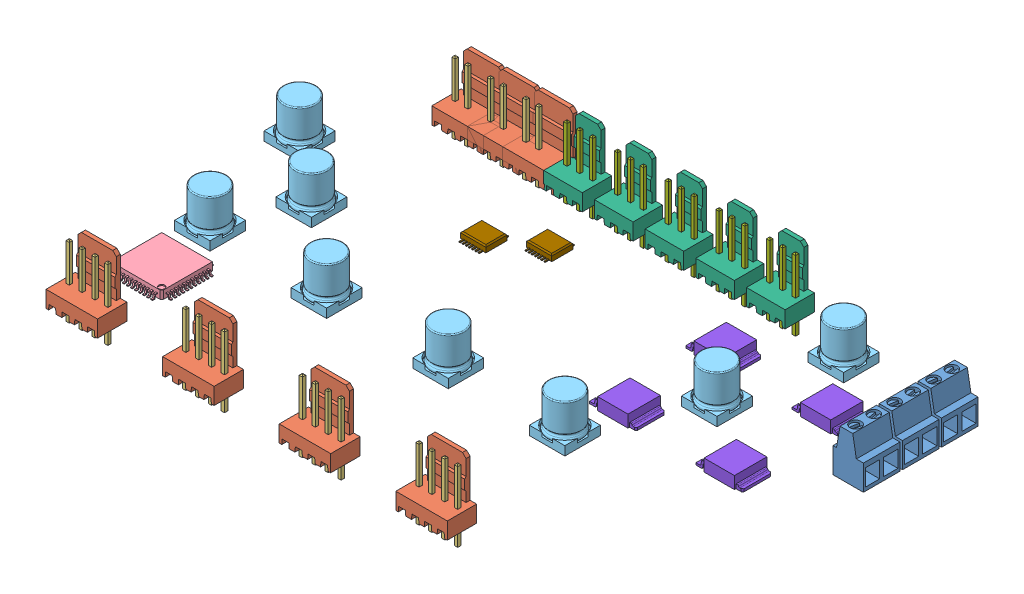
SolidWorks assembly Duex5, configuration Default. Lengths in mm.
Overall size (119.17 14.96 75.22).
91 component instances, 9 part files, 0 mates.
Components (placement in the parent):
- Duet WiFi v1-1: Duet WiFi v1 [Default] at origin (suppressed, hidden)
- 2 pole terminal block v7-1: 2 pole terminal block v7 [Default] at (58.1029 1.6572 -18.2256) x (0 0 -1) z (1 0 0) size (7.2 9 6)
- 2 pole terminal block v7-2: 2 pole terminal block v7 [Default] at (58.1029 1.6572 -10.5256) x (0 0 -1) z (1 0 0) size (7.2 9 6)
- Molex PCB 4 pin v3_1-1: Molex PCB 4 pin v3_1 [Default] at (18.0541 13.1477 49.9775) x (1 0 0) z (0 1 0) size (10.16 5.79 14.92)
  - BASE9710016-1: BASE9710016 [Default] at (2.54 2.895 -8.22) size (10.16 5.79 11.5)
  - PINO9710016-1: PINO9710016 [Default] at (1.27 3.325 -0.72) size (0.65 0.65 14.2)
  - PINO9710016-2: PINO9710016 [Default] at (3.81 3.325 -0.72) size (0.65 0.65 14.2)
  - PINO9710016-3: PINO9710016 [Default] at (6.35 3.325 -0.72) size (0.65 0.65 14.2)
  - PINO9710016-4: PINO9710016 [Default] at (8.89 3.325 -0.72) size (0.65 0.65 14.2)
- Molex PCB 4 pin v3_2-1: Molex PCB 4 pin v3_2 [Default] at (-4.9459 13.1477 49.9775) x (1 0 0) z (0 1 0) size (10.16 5.79 14.92)
  - BASE9710016-1: BASE9710016 [Default] at (2.54 2.895 -8.22) size (10.16 5.79 11.5)
  - PINO9710016-1: PINO9710016 [Default] at (1.27 3.325 -0.72) size (0.65 0.65 14.2)
  - PINO9710016-2: PINO9710016 [Default] at (3.81 3.325 -0.72) size (0.65 0.65 14.2)
  - PINO9710016-3: PINO9710016 [Default] at (6.35 3.325 -0.72) size (0.65 0.65 14.2)
  - PINO9710016-4: PINO9710016 [Default] at (8.89 3.325 -0.72) size (0.65 0.65 14.2)
- Molex PCB 4 pin v3_3-1: Molex PCB 4 pin v3_3 [Default] at (-27.9459 13.1477 49.9775) x (1 0 0) z (0 1 0) size (10.16 5.79 14.92)
  - BASE9710016-1: BASE9710016 [Default] at (2.54 2.895 -8.22) size (10.16 5.79 11.5)
  - PINO9710016-1: PINO9710016 [Default] at (1.27 3.325 -0.72) size (0.65 0.65 14.2)
  - PINO9710016-2: PINO9710016 [Default] at (3.81 3.325 -0.72) size (0.65 0.65 14.2)
  - PINO9710016-3: PINO9710016 [Default] at (6.35 3.325 -0.72) size (0.65 0.65 14.2)
  - PINO9710016-4: PINO9710016 [Default] at (8.89 3.325 -0.72) size (0.65 0.65 14.2)
- Molex PCB 4 pin v3_4-1: Molex PCB 4 pin v3_4 [Default] at (-50.9459 13.1477 49.9775) x (1 0 0) z (0 1 0) size (10.16 5.79 14.92)
  - BASE9710016-1: BASE9710016 [Default] at (2.54 2.895 -8.22) size (10.16 5.79 11.5)
  - PINO9710016-1: PINO9710016 [Default] at (1.27 3.325 -0.72) size (0.65 0.65 14.2)
  - PINO9710016-2: PINO9710016 [Default] at (3.81 3.325 -0.72) size (0.65 0.65 14.2)
  - PINO9710016-3: PINO9710016 [Default] at (6.35 3.325 -0.72) size (0.65 0.65 14.2)
  - PINO9710016-4: PINO9710016 [Default] at (8.89 3.325 -0.72) size (0.65 0.65 14.2)
- 2 pole terminal block v7-3: 2 pole terminal block v7 [Default] at (58.1029 1.6572 -2.8256) x (0 0 -1) z (1 0 0) size (7.2 9 6)
- Trinamic 2660-PA v3_4-1: Trinamic 2660-PA v3_4 [Default] at (-45.9607 1.6002 32.1353) x (-1 0 -0.000001) z (0.000001 0 -1) size (12 1.6 12)
  - Component1 (5)-1: Component1 (5) [Default] at origin size (12 1.6 12)
- PCB 7mm cap v8_1-1: PCB 7mm cap v8_1 [Default] at (21.8776 1.5787 20.4495) size (7 8 8.14)
  - Component1_3-1: Component1_3 [Default] at origin size (7 8 8.14)
- PCB 7mm cap v8_2-1: PCB 7mm cap v8_2 [Default] at (-1.1224 1.5787 20.4495) size (7 8 8.14)
  - Component1_3-1: Component1_3 [Default] at origin size (7 8 8.14)
- PCB 7mm cap v8_3-1: PCB 7mm cap v8_3 [Default] at (-25.1224 1.5787 20.4495) size (7 8 8.14)
  - Component1_3-1: Component1_3 [Default] at origin size (7 8 8.14)
- PCB 7mm cap v8_4-1: PCB 7mm cap v8_4 [Default] at (-48.1224 1.5787 20.4495) size (7 8 8.14)
  - Component1_3-1: Component1_3 [Default] at origin size (7 8 8.14)
- Molex PCB 2 pin v2 (6)_1-1: Molex PCB 2 pin v2 (6)_1 [Default] at (-44.2809 13.1082 -19.4574) x (1 0 0) z (0 1 0) size (10.16 5.79 14.92)
  - BASE9710016-1: BASE9710016 [Default] at (2.54 2.895 -8.22) size (10.16 5.79 11.5)
  - PINO9710016-1: PINO9710016 [Default] at (1.27 3.325 -0.72) size (0.65 0.65 14.2)
  - PINO9710016-2: PINO9710016 [Default] at (3.81 3.325 -0.72) size (0.65 0.65 14.2)
- Molex PCB 2 pin v2 (6)_2-1: Molex PCB 2 pin v2 (6)_2 [Default] at (-37.2809 13.1082 -19.4574) x (1 0 0) z (0 1 0) size (10.16 5.79 14.92)
  - BASE9710016-1: BASE9710016 [Default] at (2.54 2.895 -8.22) size (10.16 5.79 11.5)
  - PINO9710016-1: PINO9710016 [Default] at (1.27 3.325 -0.72) size (0.65 0.65 14.2)
  - PINO9710016-2: PINO9710016 [Default] at (3.81 3.325 -0.72) size (0.65 0.65 14.2)
- Molex PCB 2 pin v2 (6)_3-1: Molex PCB 2 pin v2 (6)_3 [Default] at (-30.2809 13.1082 -19.4574) x (1 0 0) z (0 1 0) size (10.16 5.79 14.92)
  - BASE9710016-1: BASE9710016 [Default] at (2.54 2.895 -8.22) size (10.16 5.79 11.5)
  - PINO9710016-1: PINO9710016 [Default] at (1.27 3.325 -0.72) size (0.65 0.65 14.2)
  - PINO9710016-2: PINO9710016 [Default] at (3.81 3.325 -0.72) size (0.65 0.65 14.2)
- Molex PCB 3 pin v2 v6_1-1: Molex PCB 3 pin v2 v6_1 [Default] at (-22.2009 13.1082 -19.4574) x (1 0 0) z (0 1 0) size (7.62 5.79 14.92)
  - BASE9710016_2-1: BASE9710016_2 [Default] at (2.54 2.895 -8.22) size (7.62 5.79 11.5)
  - PINO9710016_2-1: PINO9710016_2 [Default] at (1.27 3.325 -0.72) size (0.65 0.65 14.2)
  - PINO9710016_2-2: PINO9710016_2 [Default] at (3.81 3.325 -0.72) size (0.65 0.65 14.2)
  - PINO9710016_2-3: PINO9710016_2 [Default] at (6.35 3.325 -0.72) size (0.65 0.65 14.2)
- Molex PCB 3 pin v2 v6_2-1: Molex PCB 3 pin v2 v6_2 [Default] at (-12.2009 13.1082 -19.4574) x (1 0 0) z (0 1 0) size (7.62 5.79 14.92)
  - BASE9710016_2-1: BASE9710016_2 [Default] at (2.54 2.895 -8.22) size (7.62 5.79 11.5)
  - PINO9710016_2-1: PINO9710016_2 [Default] at (1.27 3.325 -0.72) size (0.65 0.65 14.2)
  - PINO9710016_2-2: PINO9710016_2 [Default] at (3.81 3.325 -0.72) size (0.65 0.65 14.2)
  - PINO9710016_2-3: PINO9710016_2 [Default] at (6.35 3.325 -0.72) size (0.65 0.65 14.2)
- Molex PCB 3 pin v2 v6_3-1: Molex PCB 3 pin v2 v6_3 [Default] at (-2.2009 13.1082 -19.4574) x (1 0 0) z (0 1 0) size (7.62 5.79 14.92)
  - BASE9710016_2-1: BASE9710016_2 [Default] at (2.54 2.895 -8.22) size (7.62 5.79 11.5)
  - PINO9710016_2-1: PINO9710016_2 [Default] at (1.27 3.325 -0.72) size (0.65 0.65 14.2)
  - PINO9710016_2-2: PINO9710016_2 [Default] at (3.81 3.325 -0.72) size (0.65 0.65 14.2)
  - PINO9710016_2-3: PINO9710016_2 [Default] at (6.35 3.325 -0.72) size (0.65 0.65 14.2)
- Molex PCB 3 pin v2 v6_4-1: Molex PCB 3 pin v2 v6_4 [Default] at (7.7991 13.1082 -19.4574) x (1 0 0) z (0 1 0) size (7.62 5.79 14.92)
  - BASE9710016_2-1: BASE9710016_2 [Default] at (2.54 2.895 -8.22) size (7.62 5.79 11.5)
  - PINO9710016_2-1: PINO9710016_2 [Default] at (1.27 3.325 -0.72) size (0.65 0.65 14.2)
  - PINO9710016_2-2: PINO9710016_2 [Default] at (3.81 3.325 -0.72) size (0.65 0.65 14.2)
  - PINO9710016_2-3: PINO9710016_2 [Default] at (6.35 3.325 -0.72) size (0.65 0.65 14.2)
- Molex PCB 3 pin v2 v6_5-1: Molex PCB 3 pin v2 v6_5 [Default] at (17.7991 13.1082 -19.4574) x (1 0 0) z (0 1 0) size (7.62 5.79 14.92)
  - BASE9710016_2-1: BASE9710016_2 [Default] at (2.54 2.895 -8.22) size (7.62 5.79 11.5)
  - PINO9710016_2-1: PINO9710016_2 [Default] at (1.27 3.325 -0.72) size (0.65 0.65 14.2)
  - PINO9710016_2-2: PINO9710016_2 [Default] at (3.81 3.325 -0.72) size (0.65 0.65 14.2)
  - PINO9710016_2-3: PINO9710016_2 [Default] at (6.35 3.325 -0.72) size (0.65 0.65 14.2)
- PCB 7mm cap v8_5-1: PCB 7mm cap v8_5 [Default] at (31.8776 1.5787 0.4495) size (7 8 8.14)
  - Component1_3-1: Component1_3 [Default] at origin size (7 8 8.14)
- PCB 7mm cap v8_6-1: PCB 7mm cap v8_6 [Default] at (36.8776 1.5787 -19.5505) size (7 8 8.14)
  - Component1_3-1: Component1_3 [Default] at origin size (7 8 8.14)
- MOSFET v9-1: MOSFET v9 [Default] at (44.8765 1.6199 -9.2021) x (0 0 1) z (-1 0 0) size (6.4 2.4 9.33)
- MOSFET v9-2: MOSFET v9 [Default] at (23.8765 1.6199 -9.2021) x (0 0 1) z (-1 0 0) size (6.4 2.4 9.33)
- MOSFET v9-3: MOSFET v9 [Default] at (23.8765 1.6199 9.7979) x (0 0 1) z (-1 0 0) size (6.4 2.4 9.33)
- MOSFET v9-4: MOSFET v9 [Default] at (44.8765 1.6199 9.7979) x (0 0 1) z (-1 0 0) size (6.4 2.4 9.33)
- PCB 7mm cap v8_7-1: PCB 7mm cap v8_7 [Default] at (-42.1224 1.5787 6.4495) size (7 8 8.14)
  - Component1_3-1: Component1_3 [Default] at origin size (7 8 8.14)
- PCB 7mm cap v8_8-1: PCB 7mm cap v8_8 [Default] at (-54.5623 1.5787 -3.6684) size (7 8 8.14)
  - Component1_3-1: Component1_3 [Default] at origin size (7 8 8.14)
- Micro P v5_1-1: Micro P v5_1 [Default] at (-11.5775 1.6187 -10.0194) x (-1 0 0) z (0 0 -1) size (5 1.2 5.8)
  - Component1 (2)-1: Component1 (2) [Default] at origin size (5 1.2 5.8)
- Micro P v5_2-1: Micro P v5_2 [Default] at (-19.5775 1.6187 -5.0194) x (-1 0 0) z (0 0 -1) size (5 1.2 5.8)
  - Component1 (2)-1: Component1 (2) [Default] at origin size (5 1.2 5.8)
